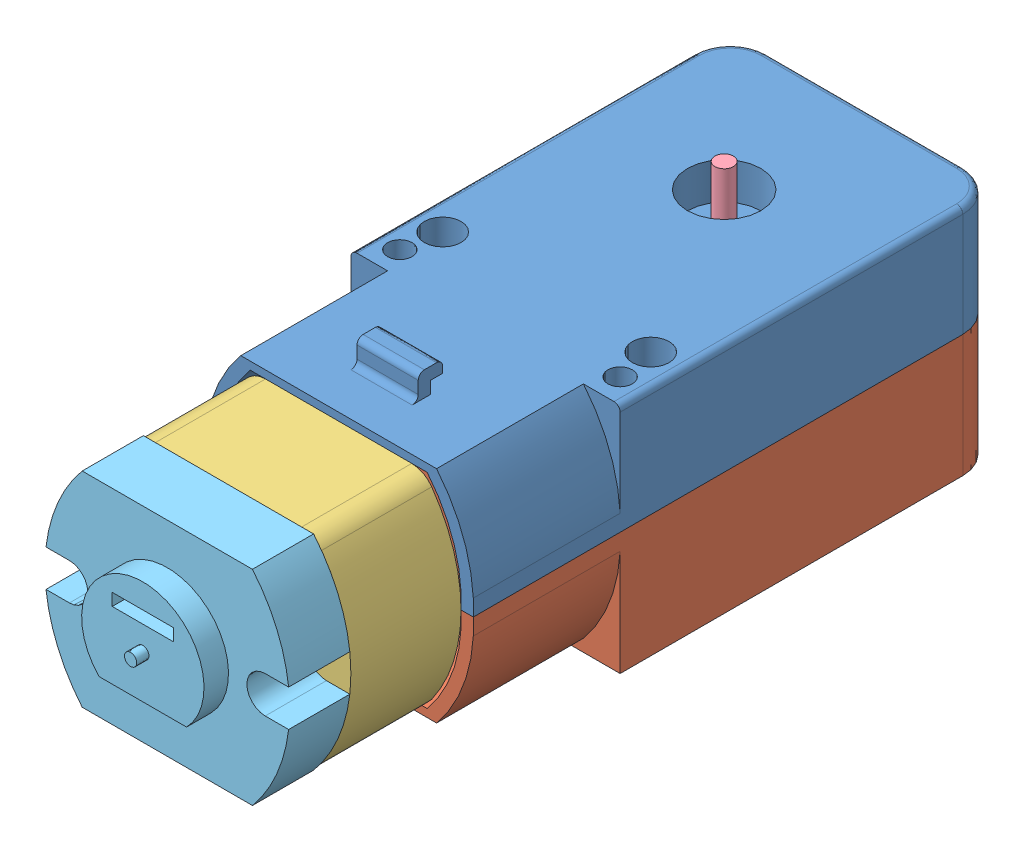
SolidWorks assembly Montagem motor, configuration Default. Lengths in mm.
Overall size (22 22.5 65).
6 component instances, 6 part files, 15 mates.
Components (placement in the parent):
- capa 1 (amarela)-2: capa 1 (amarela) [Default] at (-35.0993 65.3634 43.736) x (0 0 -1) z (1 0 0) size (48 11 22)
- capa 2 (amarela)-2: capa 2 (amarela) [Default] at (-57.0993 65.3634 43.736) x (0 0 -1) z (-1 0 0) size (48 11.5 22)
- base1 (cinza)-1: base1 (cinza) [Default] at (-46.1006 65.3628 55.736) size (20 16.72 9)
- pino 2 (cinza)-1: pino 2 (cinza) [Default] at (-46.0993 71.3634 24.236) size (1.5 5 1.5)
- Ponta (preto)-2: Ponta (preto) [Default] at (-46.1006 65.3628 64.736) x (-1 0 0) z (0 0 1) size (19.83 16.72 8)
- suporte motor (acrílico)-2: suporte motor (acrílico) [Default] at (-38.6006 55.3628 47.736) x (0 -1 0) z (-1 0 0) (suppressed, hidden)
Mates (geometry in assembly coordinates):
- Coincident8: coincident: plane of capa 1 (amarela)-2 through (-35.0993 65.3634 43.736) normal (0 -1 0); plane of capa 2 (amarela)-2 through (-57.0993 65.3634 43.736) normal (0 1 0)
- Coincident9: coincident: plane of capa 1 (amarela)-2 through (-43.5993 65.3634 7.736) normal (1 0 0); plane of capa 2 (amarela)-2 through (-43.5993 65.3634 7.736) normal (1 0 0)
- Coincident10: coincident: plane of capa 1 (amarela)-2 through (-35.0993 65.3634 7.736) normal (0 0 -1); plane of capa 2 (amarela)-2 through (-57.0993 65.3634 7.736) normal (0 0 -1)
- Coincident14: coincident: plane of capa 1 (amarela)-2 through (-53.3314 73.7228 45.736) normal (0 -1 0); plane of base1 (cinza)-1 through (-46.1006 73.7228 64.736) normal (0 1 0)
- Parallel1: parallel: cylinder of capa 1 (amarela)-2 through (-48.0819 66.0359 45.736) axis (0 0 1) radius 12; cylinder of base1 (cinza)-1 through (-49.1006 65.3628 64.736) axis (0 0 -1) radius 13
- Parallel4: parallel: cylinder of capa 1 (amarela)-2 through (-48.0819 66.0359 45.736) axis (0 0 1) radius 12; cylinder of base1 (cinza)-1 through (-49.1006 65.3628 64.736) axis (0 0 -1) radius 13
- Coincident15: coincident: point of capa 2 (amarela)-2; circle of base1 (cinza)-1
- Coincident19: coincident: circle of capa 1 (amarela)-2; circle of pino 2 (cinza)-1
- Coincident25: coincident: plane of base1 (cinza)-1 through (-46.1006 65.3628 64.736) normal (0 0 1); plane of Ponta (preto)-2 through (-46.1006 65.3628 64.736) normal (0 0 -1)
- Coincident26: coincident: line of base1 (cinza)-1 through (-52.0756 57.0028 64.736) axis (1 0 0); line of Ponta (preto)-2 through (-39.1452 57.0028 64.736) axis (-1 0 0)
- Concentric7: concentric: cylinder of base1 (cinza)-1 through (-43.1006 65.3628 64.736) axis (0 0 -1) radius 13; cylinder of Ponta (preto)-2 through (-43.1006 65.3628 69.736) axis (0 0 -1) radius 13
- Coincident34: coincident: plane of Ponta (preto)-2 through (-42.5299 61.8628 71.736) normal (0 -1 0); plane of suporte motor (acrílico)-2 through (-49.6713 61.8628 47.736) normal (0 1 0)
- Concentric8: concentric: cylinder of Ponta (preto)-2 through (-46.1006 65.3628 71.736) axis (0 0 -1) radius 5; cylinder of suporte motor (acrílico)-2 through (-46.1006 65.3628 47.736) axis (0 0 1) radius 5
- Concentric9: concentric: cylinder of Ponta (preto)-2 through (-46.1006 65.3628 71.736) axis (0 0 -1) radius 5; cylinder of suporte motor (acrílico)-2 through (-46.1006 65.3628 47.736) axis (0 0 1) radius 5
- Coincident35: coincident: plane of Ponta (preto)-2 through (-46.1006 65.3628 69.736) normal (0 0 1); plane of suporte motor (acrílico)-2 through (-53.6006 58.3628 69.736) normal (0 0 -1)
